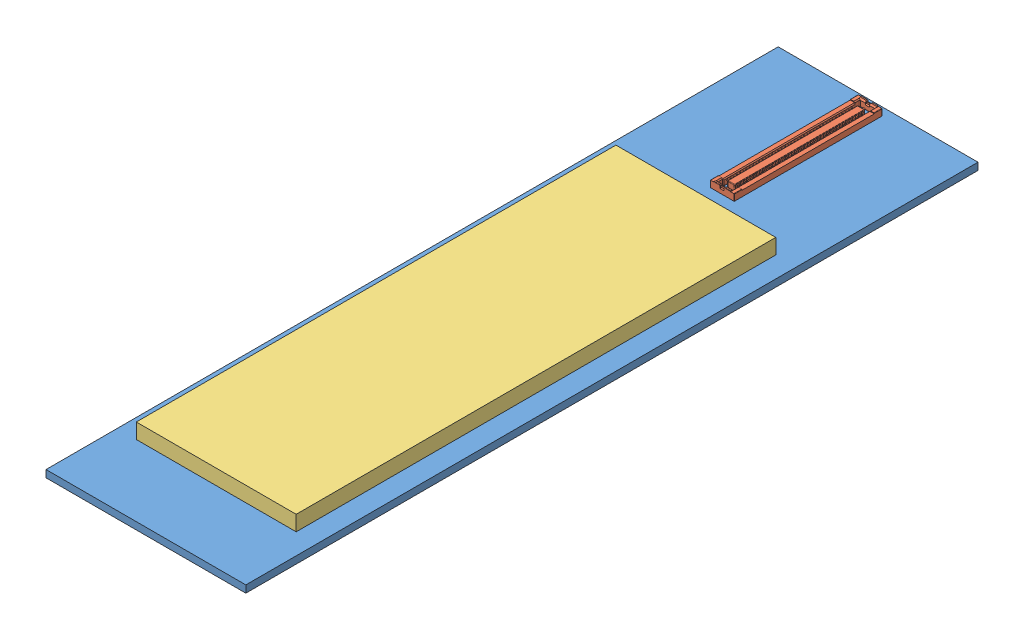
SolidWorks assembly PXL_Outer_Ladder_Driver_Board, configuration Default. Lengths in mm.
Overall size (25 2.8 91.6).
3 component instances, 3 part files, 7 mates.
Components (placement in the parent):
- PXL_Outer_Ladder_Driver_Board-1: PXL_Outer_Ladder_Driver_Board [Default] at origin size (25 0.9 91.6)
- 80pin_Header_axt580224-1: 80pin_Header_axt580224 [Default] at (0 0.63 -190.4796) x (0 0 -1) z (0 1 0) size (18.5 3.6 1.17)
- PXL_Outer_Ladder_Driver_Chips_Envelope-1: PXL_Outer_Ladder_Driver_Chips_Envelope [Default] at (-0.1 0.9 -148.0296) x (0 0 -1) z (1 0 0) size (60 1.9 20)
Mates (geometry in assembly coordinates):
- Coincident1: coordinate: point of PXL_Outer_Ladder_Driver_Board-1; point of assembly
- Distance2: distance = 1.8 mm anti-aligned: plane of PXL_Outer_Ladder_Driver_Board-1 through (-12.5 0 -109.1296) normal (0 -1 0); plane of 80pin_Header_axt580224-1 through (0.25 1.8 -199.7296) normal (0 1 0)
- Distance1: distance = 1 mm aligned: plane of 80pin_Header_axt580224-1 through (1.5 1.72 -199.7296) normal (0 0 -1); plane of PXL_Outer_Ladder_Driver_Board-1 through (-12.5 0.9 -200.7296) normal (0 0 -1)
- Coincident4: coincident: moEndPointRef_w of 80pin_Header_axt580224-1; plane of assembly
- Coincident5: coincident: plane of PXL_Outer_Ladder_Driver_Board-1 through (-12.5 0.9 -109.1296) normal (0 1 0); plane of PXL_Outer_Ladder_Driver_Chips_Envelope-1 through (-0.1 0.9 -148.0296) normal (0 -1 0)
- Distance3: distance = 2.6 mm: plane of PXL_Outer_Ladder_Driver_Chips_Envelope-1 through (9.9 2.8 -118.0296) normal (1 0 0); plane of PXL_Outer_Ladder_Driver_Board-1 through (12.5 0.9 -200.7296) normal (1 0 0)
- Distance4: distance = 22.7 mm aligned: plane of PXL_Outer_Ladder_Driver_Chips_Envelope-1 through (-10.1 2.8 -178.0296) normal (0 0 -1); plane of PXL_Outer_Ladder_Driver_Board-1 through (-12.5 0.9 -200.7296) normal (0 0 -1)
